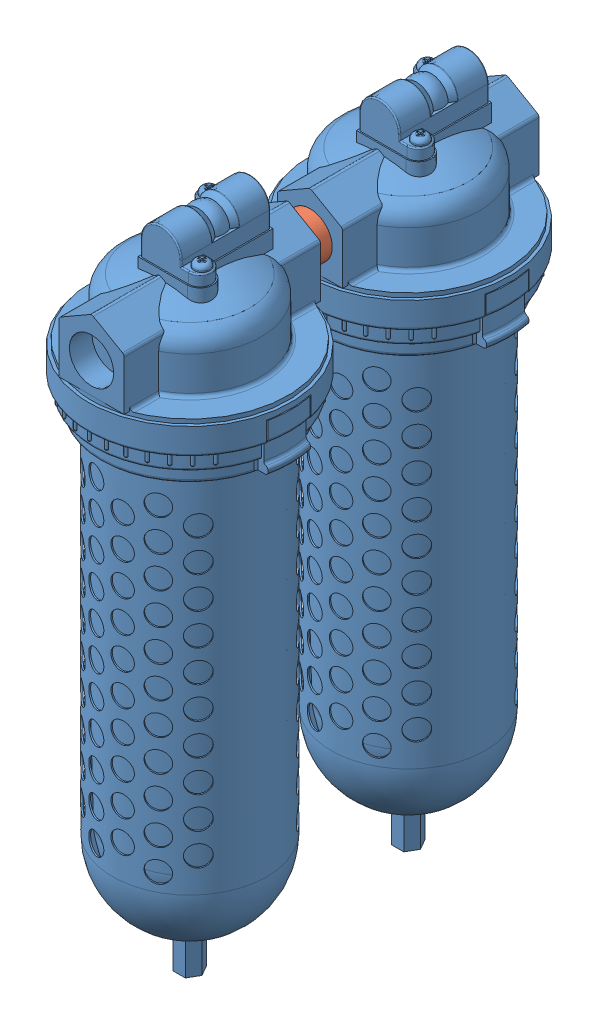
SolidWorks assembly ReadingTech_4P-150-P06-DCi, configuration Default. Lengths in mm.
Overall size (121.86 394.5 252.73).
3 component instances, 2 part files, 3 mates.
Components (placement in the parent):
- ReadingTech_3P150P06Fi-1: ReadingTech_3P150P06Fi [Default] at (69.459 -46.774 351.7688) size (121.86 394.5 121.67)
- ReadingTech_3P150P06Fi-2: ReadingTech_3P150P06Fi [Default] at (69.459 -46.774 220.7048) size (121.86 394.5 121.67)
- ReadingTech- 90,150cfm_connector_.75in-1: ReadingTech- 90,150cfm_connector_.75in [Default] at (69.459 342.227 292.8408) x (1 0 0) z (0 1 0) size (26.67 13.21 26.67)
Mates (geometry in assembly coordinates):
- Coincident1: coincident anti-aligned: circle of ReadingTech_3P150P06Fi-2; circle of ReadingTech- 90,150cfm_connector_.75in-1
- Coincident2: coincident aligned: circle of ReadingTech_3P150P06Fi-1; circle of ReadingTech- 90,150cfm_connector_.75in-1
- Coincident3: coincident aligned: plane of ReadingTech_3P150P06Fi-1 through (89.017 354.927 410.6968) normal (1 0 0); plane of ReadingTech_3P150P06Fi-2 through (89.017 354.927 279.6328) normal (1 0 0)
